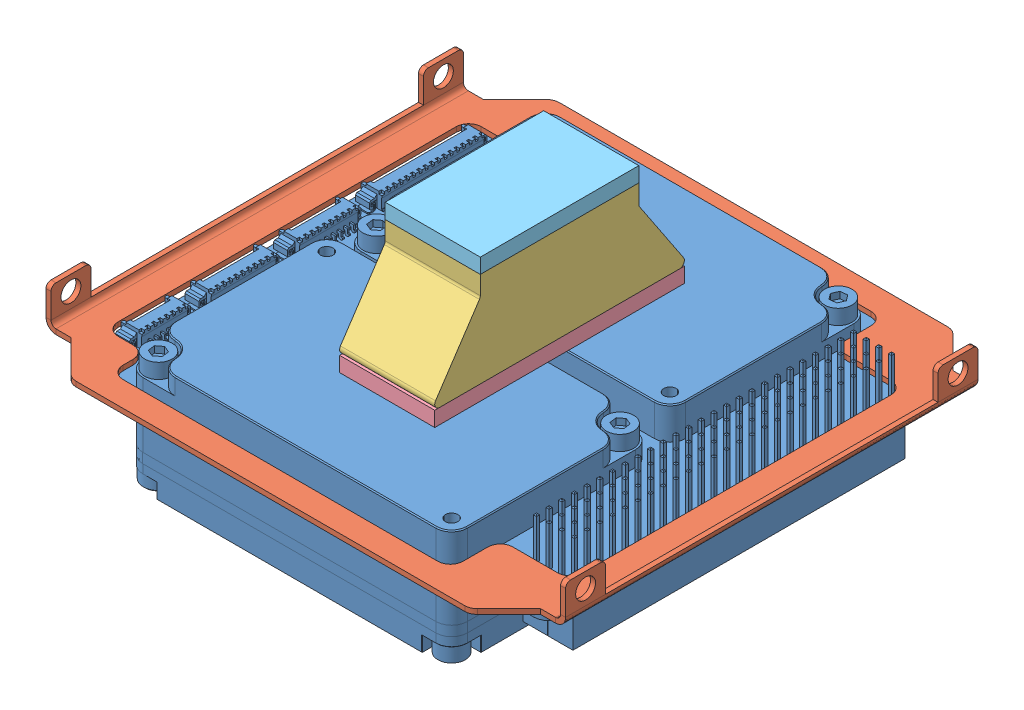
SolidWorks assembly Spirit2U - Transceiver Shelf, configuration Default. Lengths in mm.
Overall size (104.07 48.4 96.74).
6 component instances, 5 part files, 7 mates.
Components (placement in the parent):
- Transceiver-1: Transceiver [Default] at (15.6415 61.9277 -96.8705) x (1 0 0) z (0 -1 0) size (92.9 88.87 25.05)
- Spirit2U Tranceiver Shelf-1: Spirit2U Tranceiver Shelf [Default] at origin size (104.07 8 96.74)
- Transceiver HS Assembly-1: Transceiver HS Assembly [Default] at (52.036 17.017 -41.3) x (0 0 1) z (-1 0 0) size (50.01 25 19.05)
  - Transceiver HS-1: Transceiver HS [Default] at origin size (50.01 19 19.05)
  - Transceiver HS Epoxy Bottom-1: Transceiver HS Epoxy Bottom [Default] at (0 -12.5 0) size (50 3 19.05)
  - Transceiver HS Epoxy Top-1: Transceiver HS Epoxy Top [Default] at (0 9.5 0) size (31.75 3 19.05)
Mates (geometry in assembly coordinates):
- Distance9: distance = 1 mm: plane of Transceiver-1 through (12.7664 -2 -87.9017) normal (0 1 0); plane of Spirit2U Tranceiver Shelf-1 through (0 -1 0) normal (0 -1 0)
- Distance10: distance = 5 mm: plane of Spirit2U Tranceiver Shelf-1 through (104.072 0 0) normal (1 0 0); plane of Transceiver-1 through (99.072 -2 -4.8961) normal (1 0 0)
- Distance12: distance = 3.8 mm: point of Transceiver-1; plane of Spirit2U Tranceiver Shelf-1 through (92.0009 -1 -89.6711) normal (0 0 -1)
- Coincident1: coordinate: point of Spirit2U Tranceiver Shelf-1; point of assembly
- Coincident6: coincident: plane of Transceiver HS Assembly-1/Transceiver HS-1 through (52.036 17.017 -41.3) normal (-1 0 0)
- Coincident4: coincident: plane of Transceiver HS Assembly-1 through (56.036 17.017 -41.3) normal (0 0 1); plane of assembly through (0 0 -41.3) normal (0 0 -1)
- Coincident5: coincident: plane of Transceiver-1 through (17.092 4.517 -42.8811) normal (0 1 0); plane of Transceiver HS Assembly-1/Transceiver HS Epoxy Bottom-1 through (56.036 4.517 -41.3) normal (0 -1 0)
